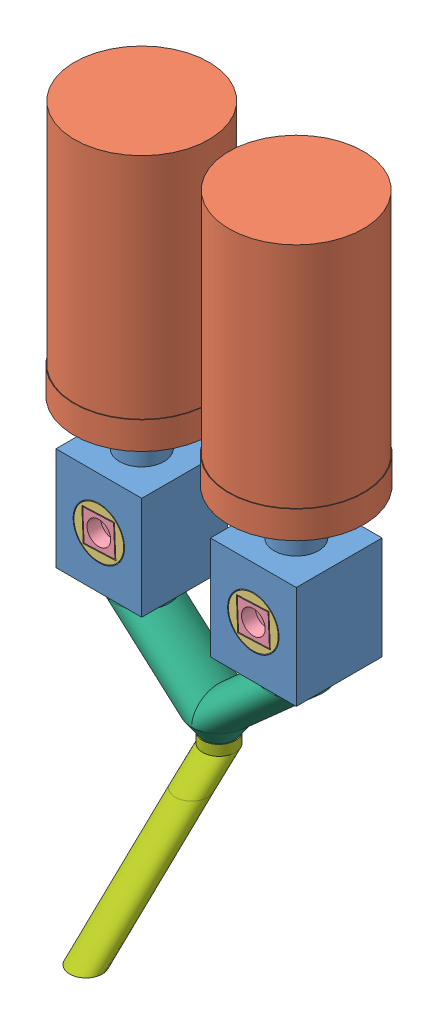
SolidWorks assembly EnsamblajePowderConEstructura, configuration Predeterminado. Lengths in mm.
Overall size (171.88 376.5 126.22).
14 component instances, 7 part files, 7 mates.
Components (placement in the parent):
- EnsamblajePowderDispenser-1: EnsamblajePowderDispenser [Predeterminado] at (-46.3974 -19.9468 185.5) size (81.88 245.5 81.88)
  - CajaDelMedio-1: CajaDelMedio [Predeterminado] at (7.2227 -22.3574 60) size (50 91.5 50)
  - Botella-1: Botella [Predeterminado] at (7.2227 23.1426 60) x (0.999311 0 0.037103) z (-0.037103 0 0.999311) size (79 190 79)
  - CilindroCentral-1: CilindroCentral [Predeterminado] at (7.2227 7.6426 39) x (0 0 1) z (-0.043 0.999075 0) size (46 29 29)
  - CuadradoTorque-1: CuadradoTorque [Predeterminado] at (7.2227 7.6426 75) x (-0.999075 -0.043 0) z (0 0 1) size (18 18 10)
  - EjeSoporte-1: EjeSoporte [Predeterminado] at (7.2227 7.6426 33) x (1 0 0) z (0 -1 0) size (12 14 12)
- PowderTuboFinal1DOS-1: PowderTuboFinal1DOS [Predeterminado] at (50.8253 -52.3042 245.5) size (122 65 32)
- PowderTuboFinal2-1: PowderTuboFinal2 [Predeterminado] at (5.4246 -123.3042 261.0585) x (0.025741 0 -0.999669) z (0.999669 0 0.025741) size (94.57 81 19)
- EnsamblajePowderDispenser-3: EnsamblajePowderDispenser [Predeterminado] at (43.6026 -19.9468 185.5) size (81.88 245.5 81.88)
  - CajaDelMedio-1: CajaDelMedio [Predeterminado] at (7.2227 -22.3574 60) size (50 91.5 50)
  - Botella-1: Botella [Predeterminado] at (7.2227 23.1426 60) x (0.999311 0 0.037103) z (-0.037103 0 0.999311) size (79 190 79)
  - CilindroCentral-1: CilindroCentral [Predeterminado] at (7.2227 7.6426 39) x (0 0 1) z (-0.043 0.999075 0) size (46 29 29)
  - CuadradoTorque-1: CuadradoTorque [Predeterminado] at (7.2227 7.6426 75) x (-0.999075 -0.043 0) z (0 0 1) size (18 18 10)
  - EjeSoporte-1: EjeSoporte [Predeterminado] at (7.2227 7.6426 33) x (1 0 0) z (0 -1 0) size (12 14 12)
Mates (geometry in assembly coordinates):
- Coincidente1: coincident: plane of assembly; plane of assembly; plane of EnsamblajePowderDispenser-1/CajaDelMedio-1 through (-39.1747 -42.3042 245.5) normal (0 -1 0); plane of PowderTuboFinal1DOS-1 through (-39.1747 -42.3042 245.5) normal (0 1 0)
- Concéntrica1: concentric: cylinder of assembly; cylinder of assembly; cylinder of EnsamblajePowderDispenser-1/CajaDelMedio-1 through (-39.1747 -52.3042 245.5) axis (0 1 0) radius 13; cylinder of PowderTuboFinal1DOS-1 through (-39.1747 -42.3042 245.5) axis (0 -1 0) radius 16
- Concéntrica3: concentric: cylinder of assembly; cylinder of assembly; cylinder of PowderTuboFinal1DOS-1 through (5.8253 -107.3042 245.498) axis (0 1 0) radius 8.998; cylinder of PowderTuboFinal2-1 through (5.8253 -102.3042 245.498) axis (0 -1 0) radius 7.5
- Distancia1: distance = 5 mm: plane of assembly; plane of assembly; plane of PowderTuboFinal2-1 through (5.8253 -102.3042 245.498) normal (0 1 0); plane of PowderTuboFinal1DOS-1 through (5.8253 -107.3042 245.498) normal (0 -1 0)
- Concéntrica4: concentric: cylinder of assembly; cylinder of assembly; cylinder of PowderTuboFinal1DOS-1 through (50.8253 -42.3042 245.5) axis (0 -1 0) radius 16; cylinder of EnsamblajePowderDispenser-3/CajaDelMedio-1 through (50.8253 -52.3042 245.5) axis (0 1 0) radius 13
- Coincidente2: coincident: plane of assembly; plane of assembly; plane of EnsamblajePowderDispenser-1/CajaDelMedio-1 through (-64.1747 17.6958 270.5) normal (0 0 1); plane of EnsamblajePowderDispenser-3/CajaDelMedio-1 through (25.8253 17.6958 270.5) normal (0 0 1)
- Coincidente3: coincident: plane of assembly; plane of assembly; plane of EnsamblajePowderDispenser-1/CajaDelMedio-1 through (-39.1747 -42.3042 245.5) normal (0 -1 0); plane of EnsamblajePowderDispenser-3/CajaDelMedio-1 through (50.8253 -42.3042 245.5) normal (0 -1 0)
